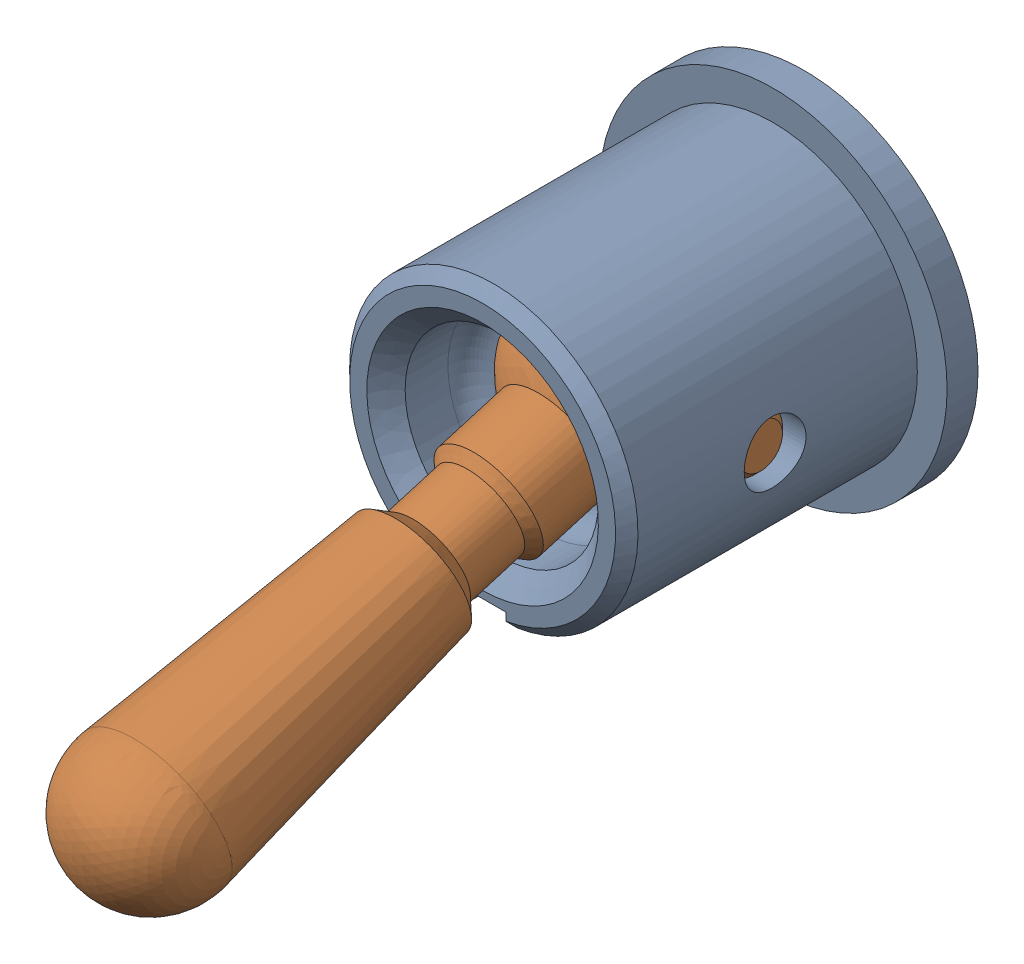
SolidWorks assembly MS Toggle Switch Sealed 2-Position Ref v2, configuration Default. Lengths in mm.
Overall size (14.29 17.66 30.89).
2 component instances, 2 part files, 0 mates.
Components (placement in the parent):
- Toggle Threads Sealed Ref-1: Toggle Threads Sealed Ref [Default] at (-25.4 83.058 -5.3811) size (14.29 14.29 13.21)
- Toggle Lever Sealed Ref-1: Toggle Lever Sealed Ref [Default] at (-25.4 84.7172 -5.1405) x (1 0 0) z (0 -0.284015 0.95882) size (10.67 7.94 27.59)
